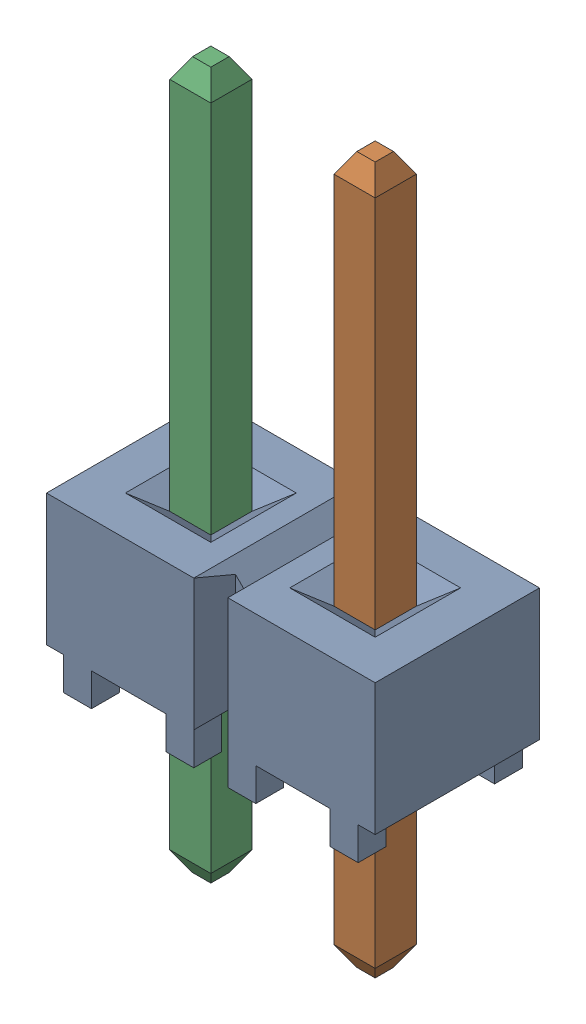
SolidWorks assembly C-L13-1X2_HEADER_ASM, configuration Default. Lengths in mm.
Overall size (5.08 10.92 2.54).
3 component instances, 2 part files, 0 mates.
Components (placement in the parent):
- C-HEADER-2PIN-BODY-1: C-HEADER-2PIN-BODY [Default] at origin size (5.08 2.54 2.54)
- C-T-HEADER-PIN-1: C-T-HEADER-PIN [Default] at (-6.35 -2.0599 0) x (0 0 1) z (-1 0 0) size (0.64 10.92 0.64)
- C-T-HEADER-PIN-2: C-T-HEADER-PIN [Default] at (-8.89 -2.0599 0) x (0 0 1) z (-1 0 0) size (0.64 10.92 0.64)
